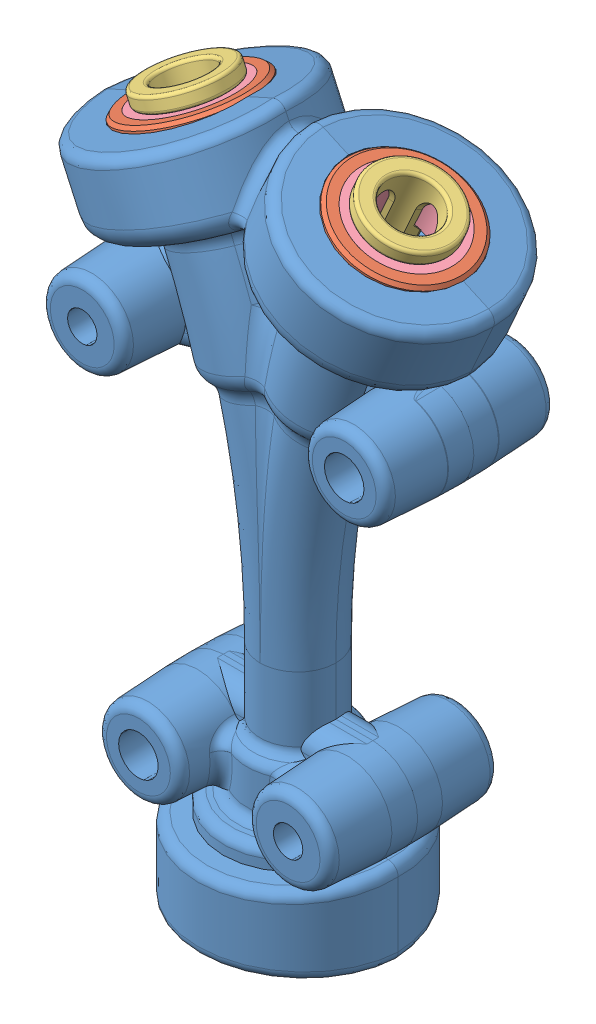
SolidWorks assembly 70629 Splitter Assembly, configuration Default. Lengths in mm.
Overall size (32.12 57.03 16.73).
10 component instances, 4 part files, 18 mates.
Components (placement in the parent):
- 70625 Splitter - Slim Cartridge - Longer Merge with Interference-1: 70625 Splitter - Slim Cartridge - Longer Merge with Interference [Default] at origin size (31.57 55.22 16.13)
- 70620 PTC Splitter Adapter - .040-1: 70620 PTC Splitter Adapter - .040 [Default] at (-8.709 24.3512 0) x (0.526461 0.237684 0.816299) z (-0.74399 -0.335893 0.577629) size (12 4.57 12)
- 70620 PTC Splitter Adapter - .040-2: 70620 PTC Splitter Adapter - .040 [Default] at (8.709 24.3512 0) x (0.90698 -0.409479 0.098559) z (-0.089829 0.040555 0.995131) size (12 4.57 12)
- 70620 PTC Splitter Adapter - .040-3: 70620 PTC Splitter Adapter - .040 [Default] at (0 -28.008 0) x (-0.837169 0 -0.546944) z (-0.546944 0 0.837169) size (12 4.57 12)
- John Guest Plastic Insert_Model Only-3: John Guest Plastic Insert_Model Only [Default] at (0 -22.578 0) x (0.623537 0 0.781793) z (0.781793 0 -0.623537) size (6.92 6.66 6.92)
- John Guest Brass Insert_Model Only-1: John Guest Brass Insert_Model Only [Default] at (0 -24.158 0) x (0.984397 0 0.17596) z (0 -1 0) size (8 8 3.85)
- John Guest Brass Insert_Model Only-2: John Guest Brass Insert_Model Only [Default] at (8.709 24.3512 0) x (0.897197 -0.405062 0.17596) z (-0.411482 -0.911418 0) size (8 8 3.85)
- John Guest Brass Insert_Model Only-3: John Guest Brass Insert_Model Only [Default] at (-8.709 24.3512 0) x (0.897197 0.405062 0.17596) z (0.411482 -0.911418 0) size (8 8 3.85)
- John Guest Plastic Insert_Model Only-4: John Guest Plastic Insert_Model Only [Default] at (-6.4747 19.4022 0) x (0.908001 0.40994 0.086508) z (-0.078845 -0.035596 0.996251) size (6.92 6.66 6.92)
- John Guest Plastic Insert_Model Only-5: John Guest Plastic Insert_Model Only [Default] at (6.4747 19.4022 0) x (0.90292 -0.407646 0.136238) z (-0.12417 0.05606 0.990676) size (6.92 6.66 6.92)
Mates (geometry in assembly coordinates):
- Concentric1: concentric aligned: cylinder of 70625 Splitter - Slim Cartridge - Longer Merge with Interference-1 through (-7.6639 22.0362 0) axis (-0.411482 0.911418 0) radius 5.0546; cylinder of 70620 PTC Splitter Adapter - .040-1 through (-8.709 24.3512 0) axis (-0.411482 0.911418 0) radius 4
- Coincident1: coincident anti-aligned: plane of 70625 Splitter - Slim Cartridge - Longer Merge with Interference-1 through (-7.6639 22.0362 0) normal (0.411482 -0.911418 0); plane of 70620 PTC Splitter Adapter - .040-1 through (-5.0231 23.2284 4.0946) normal (-0.411482 0.911418 0)
- Concentric2: concentric aligned: cylinder of 70625 Splitter - Slim Cartridge - Longer Merge with Interference-1 through (7.6639 22.0362 0) axis (0.411482 0.911418 0) radius 5.0546; cylinder of 70620 PTC Splitter Adapter - .040-2 through (8.709 24.3512 0) axis (0.411482 0.911418 0) radius 4
- Coincident2: coincident anti-aligned: plane of 70625 Splitter - Slim Cartridge - Longer Merge with Interference-1 through (7.6639 22.0362 0) normal (-0.411482 -0.911418 0); plane of 70620 PTC Splitter Adapter - .040-2 through (12.2133 19.9823 0.4944) normal (0.411482 0.911418 0)
- Concentric3: concentric aligned: cylinder of 70625 Splitter - Slim Cartridge - Longer Merge with Interference-1 through (0 -25.468 0) axis (0 -1 0) radius 5.27; cylinder of 70620 PTC Splitter Adapter - .040-3 through (0 -28.008 0) axis (0 -1 0) radius 6
- Coincident3: coincident anti-aligned: plane of 70625 Splitter - Slim Cartridge - Longer Merge with Interference-1 through (0 -25.468 0) normal (0 1 0); plane of 70620 PTC Splitter Adapter - .040-3 through (-4.1992 -25.468 -2.7435) normal (0 -1 0)
- Concentric4: concentric anti-aligned: cylinder of 70620 PTC Splitter Adapter - .040-3 through (0 -28.008 0) axis (0 -1 0) radius 4; cylinder of John Guest Plastic Insert_Model Only-3 through (0 -22.578 0) axis (0 1 0) radius 2.4
- Distance1: distance = 0 mm anti-aligned: plane of 70620 PTC Splitter Adapter - .040-3 through (-3.3487 -28.008 -2.1878) normal (0 -1 0); plane of John Guest Plastic Insert_Model Only-3 through (1.4965 -28.008 1.8763) normal (0 1 0)
- Concentric6: concentric anti-aligned: cylinder of 70620 PTC Splitter Adapter - .040-3 through (0 -28.008 0) axis (0 -1 0) radius 4; cylinder of John Guest Brass Insert_Model Only-1 through (0 -28.008 0) axis (0 1 0) radius 4
- Coincident5: coincident aligned: plane of 70620 PTC Splitter Adapter - .040-3 through (-3.3487 -28.008 -2.1878) normal (0 -1 0); plane of John Guest Brass Insert_Model Only-1 through (0 -28.008 0) normal (0 -1 0)
- Concentric7: concentric aligned: cylinder of 70620 PTC Splitter Adapter - .040-2 through (8.709 24.3512 0) axis (0.411482 0.911418 0) radius 4; cylinder of John Guest Brass Insert_Model Only-2 through (7.1248 20.8422 0) axis (0.411482 0.911418 0) radius 3
- Concentric8: concentric aligned: cylinder of 70620 PTC Splitter Adapter - .040-1 through (-8.709 24.3512 0) axis (-0.411482 0.911418 0) radius 4; cylinder of John Guest Brass Insert_Model Only-3 through (-7.1248 20.8422 0) axis (-0.411482 0.911418 0) radius 3
- Coincident6: coincident aligned: plane of 70620 PTC Splitter Adapter - .040-1 through (-6.6032 25.3019 3.2652) normal (-0.411482 0.911418 0); plane of John Guest Brass Insert_Model Only-3 through (-8.709 24.3512 0) normal (-0.411482 0.911418 0)
- Coincident7: coincident aligned: plane of 70620 PTC Splitter Adapter - .040-2 through (12.337 22.7133 0.3942) normal (0.411482 0.911418 0); plane of John Guest Brass Insert_Model Only-2 through (8.709 24.3512 0) normal (0.411482 0.911418 0)
- Concentric9: concentric anti-aligned: cylinder of John Guest Brass Insert_Model Only-2 through (7.1248 20.8422 0) axis (0.411482 0.911418 0) radius 3; cylinder of John Guest Plastic Insert_Model Only-5 through (6.4747 19.4022 0) axis (-0.411482 -0.911418 0) radius 2.4
- Concentric10: concentric anti-aligned: cylinder of John Guest Brass Insert_Model Only-3 through (-7.1248 20.8422 0) axis (-0.411482 0.911418 0) radius 3; cylinder of John Guest Plastic Insert_Model Only-4 through (-6.4747 19.4022 0) axis (0.411482 -0.911418 0) radius 2.4
- Coincident8: coincident anti-aligned: plane of John Guest Brass Insert_Model Only-3 through (-8.709 24.3512 0) normal (-0.411482 0.911418 0); plane of John Guest Plastic Insert_Model Only-4 through (-6.5298 25.3351 0.2076) normal (0.411482 -0.911418 0)
- Coincident9: coincident anti-aligned: plane of John Guest Brass Insert_Model Only-2 through (8.709 24.3512 0) normal (0.411482 0.911418 0); plane of John Guest Plastic Insert_Model Only-5 through (10.876 23.3729 0.327) normal (-0.411482 -0.911418 0)
